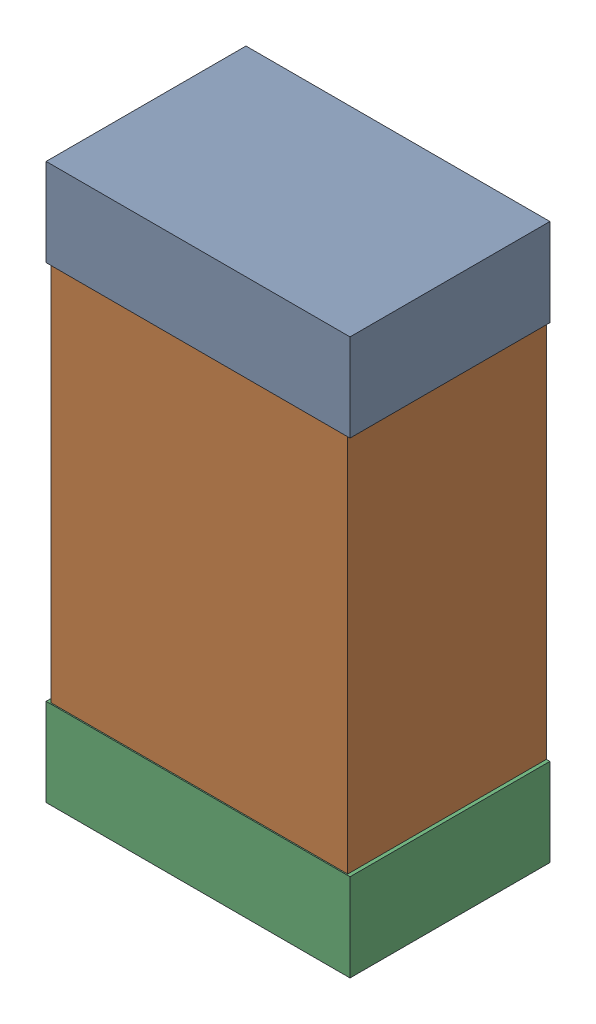
SolidWorks assembly RFBTKanaloa_v2.0.0_Power_1, configuration Default. Lengths in mm.
Overall size (1.3 2.38 0.85).
6 component instances, 2 part files, 0 mates.
Components (placement in the parent):
- 330415056-1: 330415056 [Default] at (49.022 53.832 0) size (1.3 0.38 0.85)
  - Extruded_2-1: Extruded_2 [Default] at origin size (1.3 0.38 0.85)
- 334787376-1: 334787376 [Default] at (49.022 52.832 0) size (1.27 2.2 0.85)
  - Extruded_16-1: Extruded_16 [Default] at origin size (1.27 2.2 0.85)
- 330415056-2: 330415056 [Default] at (49.022 51.832 0) size (1.3 0.38 0.85)
  - Extruded_2-1: Extruded_2 [Default] at origin size (1.3 0.38 0.85)
